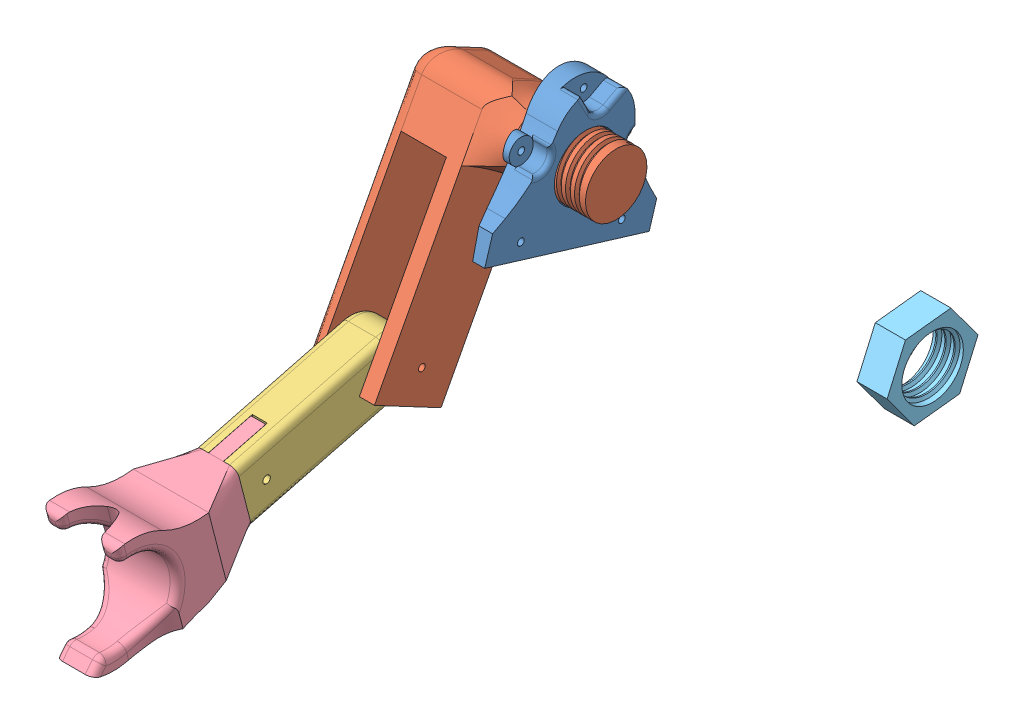
SolidWorks assembly BRAÇO NA PLATAFORMA, configuration Valor predeterminado. Lengths in mm.
Overall size (332.4 258.17 350.95).
5 component instances, 5 part files, 7 mates.
Components (placement in the parent):
- Plataforma-1: Plataforma [Valor predeterminado] at (-178.0833 -257.3784 203.2815) x (1 0 0) z (0 0.291661 0.956522) size (26.18 86.84 114)
- Braço-1: Braço [Valor predeterminado] at (-353.9799 -189.8054 56.4051) x (0 0.883356 -0.468703) z (0 0.468703 0.883356) size (168.75 120 50.02)
- antebraço 2-1: antebraço 2 [Valor predeterminado] at (-364.9799 -177.2832 54.4297) x (0 -0.25016 0.968204) z (-1 0 0) size (120 40 28)
- mão versao 2-1: mão versao 2 [Valor predeterminado] at (-353.9799 -197.1257 162.9153) x (-1 0 0) z (0 0.25016 -0.968204) size (52.99 82 139.15)
- ROSCA-1: ROSCA [Valor predeterminado] at (-74.23 -49.5595 10.2928) x (0 0.694085 0.719893) z (-1 0 0) size (59.76 56.85 22.43)
Mates (geometry in assembly coordinates):
- Concêntrico9: concentric aligned: circle of Braço-1; circle of antebraço 2-1
- Largura1: width aligned: plane of Braço-1 through (-403.9799 -166.3702 100.5729) normal (-1 0 0); plane of antebraço 2-1 through (-353.9799 -17.9664 21.8309) normal (1 0 0); plane of Braço-1 through (-392.9799 -177.2832 54.4297) normal (-1 0 0); plane of antebraço 2-1 through (-364.9799 -177.2832 54.4297) normal (1 0 0)
- Concêntrico11: concentric aligned: cylinder of Plataforma-1 through (-328.9104 -49.5595 10.2928) axis (1 0 0) radius 21; cylinder of Braço-1 through (-353.9799 -49.5595 10.2928) axis (1 0 0) radius 20.4
- Coincidente1: coincident anti-aligned: plane of Plataforma-1 through (-304.0133 -38.9436 -121.441) normal (1 0 0); plane of ROSCA-1 through (-94.23 -49.5595 10.2928) normal (-1 0 0)
- Concêntrico12: concentric aligned: circle of Braço-1; circle of ROSCA-1
- Coincidente2: coincident anti-aligned: plane of antebraço 2-1 through (-392.9799 -207.3024 170.6143) normal (0 -0.25016 0.968204); plane of mão versao 2-1 through (-387.9799 -202.4614 171.8651) normal (0 0.25016 -0.968204)
- Coincidente3: coincident: point of antebraço 2-1; unknown of mão versao 2-1
